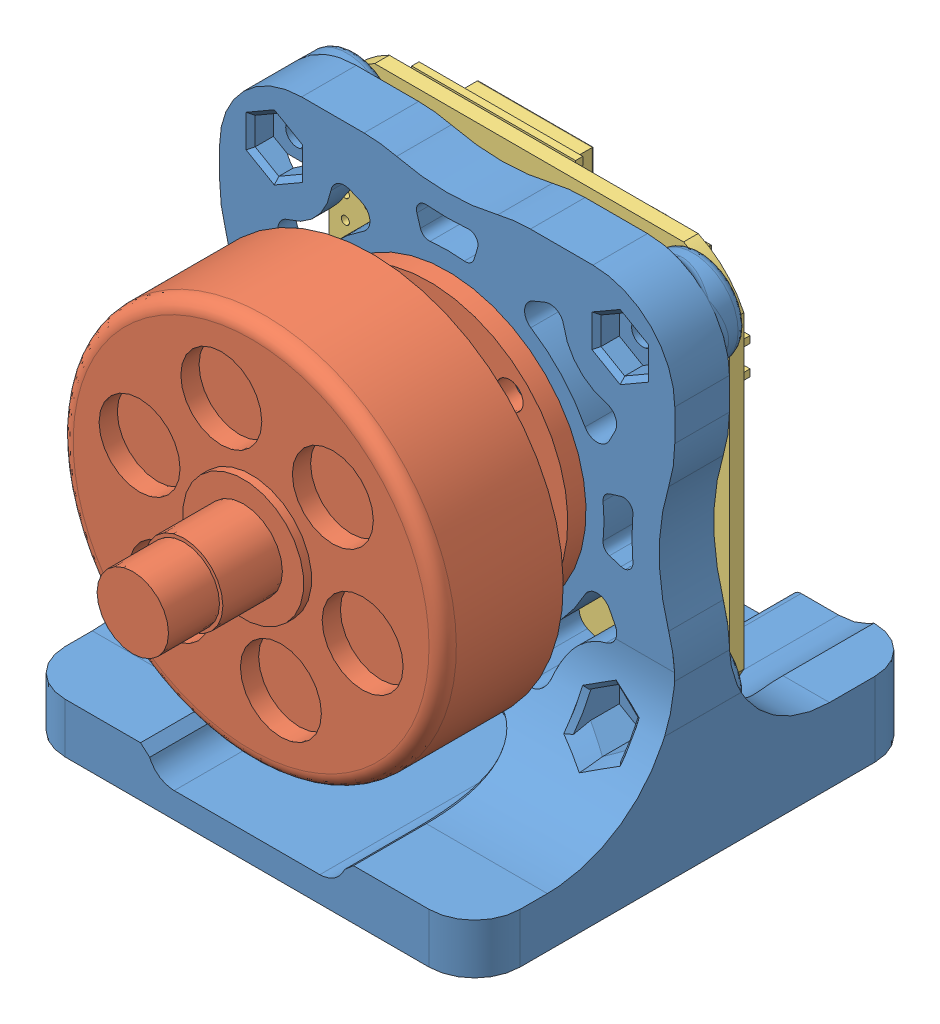
SolidWorks assembly Assemb, configuration Default. Lengths in mm.
Overall size (59.54 59.77 61.55).
3 component instances, 3 part files, 6 mates.
Components (placement in the parent):
- Test Station 2.6 (YUNM + RS485)-1: Test Station 2.6 (YUNM + RS485) [Predeterminado] at (11.2885 32.5274 44.518) size (50 53.8 49)
- YUNEEC YUMN4234 B-1: YUNEEC YUMN4234 B [Predeterminado] at (11.2885 32.5274 55.818) x (0.707107 -0.707107 0) z (-0.707107 -0.707107 0) size (42.1 37.25 42.1)
- DAGOR 2.4 Alpha-1: DAGOR 2.4 Alpha [Default] at (11.2886 32.5274 38.518) x (-1 -0.000004 0) z (0 0 -1) size (43.97 43.97 6.12)
Mates (geometry in assembly coordinates):
- Concentric1: concentric aligned: cylinder of Test Station 2.1-1 through (20.1274 41.3663 20.518) axis (0 0 1) radius 1.7; cylinder of YUNEEC YUMN4234 B-1 through (20.1274 41.3663 47.518) axis (0 0 1) radius 1.5
- Concentric2: concentric aligned: cylinder of Test Station 2.1-1 through (2.4497 23.6886 20.518) axis (0 0 1) radius 1.7; cylinder of YUNEEC YUMN4234 B-1 through (2.4497 23.6886 47.518) axis (0 0 1) radius 1.5
- Coincident1: coincident anti-aligned: plane of Test Station 2.1-1 through (-4.7149 48.5309 47.518) normal (0 0 1); plane of YUNEEC YUMN4234 B-1 through (11.2885 32.5274 47.518) normal (0 0 -1)
- Concentric3: concentric anti-aligned: cylinder of Test Station 2.1-1 through (-7.7115 50.0274 41.518) axis (0 0 1) radius 1.25; cylinder of DAGOR 2.4 Alpha-1 through (-7.7115 50.0274 38.518) axis (0 0 -1) radius 1.3
- Concentric4: concentric anti-aligned: cylinder of Test Station 2.1-1 through (30.2885 15.0274 41.518) axis (0 0 1) radius 1.25; cylinder of DAGOR 2.4 Alpha-1 through (30.2887 15.0273 38.518) axis (0 0 -1) radius 1.3
- Coincident2: coincident anti-aligned: plane of Test Station 2.1-1 through (30.2885 15.0274 38.518) normal (0 0 -1); plane of DAGOR 2.4 Alpha-1 through (11.2886 32.5274 38.518) normal (0 0 1)
